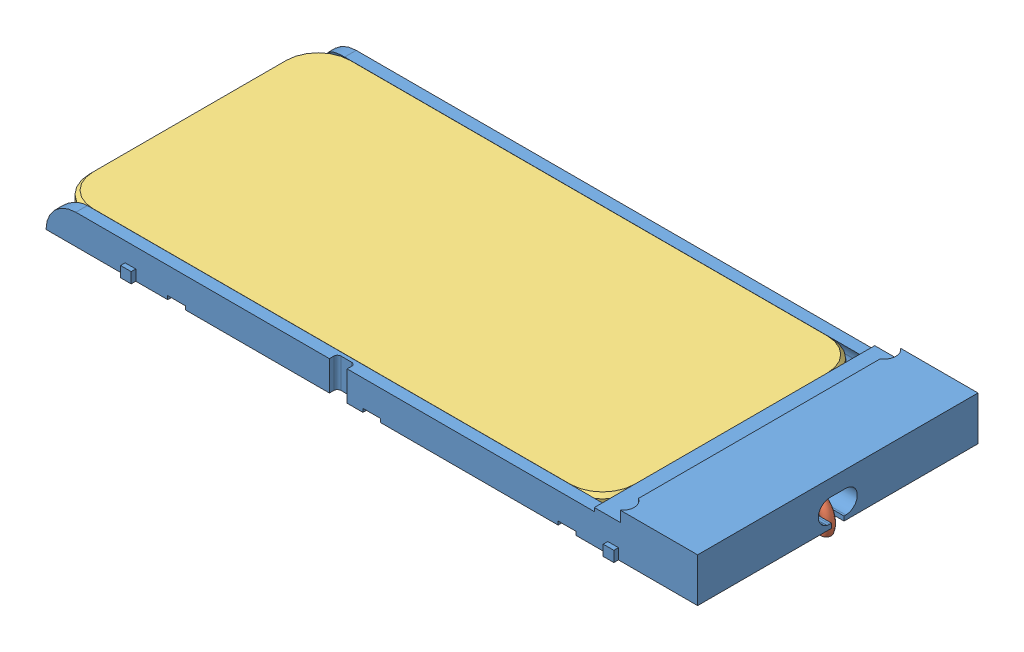
SolidWorks assembly phone-mount, configuration Default. Lengths in mm.
Overall size (183.95 29.2 81.6).
3 component instances, 3 part files, 9 mates.
Components (placement in the parent):
- phone-mount-1: phone-mount [Default] at origin size (183.95 25.78 81.6)
- phone-usb-cable-1: phone-usb-cable [Default] at (62.7 4.5 0) x (0 0 1) z (-1 0 0) size (10.6 11.2 33.23)
- phone-1: phone [Default] at (-14.55 1 0) size (154.5 8 74.4)
Mates (geometry in assembly coordinates):
- Width1: width: plane of phone-mount-1 through (57.7559 0 19.725) normal (0 0 1); plane of phone-mount-1 through (57.7559 0 30.275) normal (0 0 -1); plane of ? through (81.25 7.6 19.925) normal (0 0 -1); plane of ? through (81.25 7.6 30.075) normal (0 0 1)
- Width2: width: plane of phone-mount-1 through (57.7559 4.8 0) normal (0 1 0); plane of phone-mount-1 through (57.7559 10.4 0) normal (0 -1 0); plane of ? through (81.25 5 25) normal (0 -1 0); plane of ? through (81.25 10.2 25) normal (0 1 0)
- Coincident1: coincident: plane of phone-mount-1 through (70.5 0 0) normal (1 0 0); plane of ? through (70.5 7.6 25) normal (-1 0 0)
- Coincident2: coincident: plane of phone-mount-1 through (62.7 0 0) normal (-1 0 0); plane of phone-usb-cable-1 through (62.7 4.5 2.2) normal (-1 0 0)
- Width3: width: plane of phone-mount-1 through (91.801 1.25 0) normal (0 1 0); plane of phone-mount-1 through (91.801 7.75 0) normal (0 -1 0); plane of phone-usb-cable-1 through (77.5 7.6 2.2) normal (0 1 0); plane of phone-usb-cable-1 through (77.5 1.4 2.2) normal (0 -1 0)
- Coincident3: coincident: plane of phone-mount-1 through (0 0 0) normal (0 0 1); plane of assembly through (0 0 0) normal (0 0 1)
- Coincident4: coincident: plane of phone-usb-cable-1 through (62.7 4.5 0) normal (0 0 1); plane of assembly through (0 0 0) normal (0 0 1)
- Coincident5: coincident: line of phone-usb-cable-1 through (-11.9966 49.8907 4.5) axis (0 -1 0); line of phone-1 through (-31.6904 70.391 4.5) axis (0 1 0)
- Coincident6: coincident: plane of phone-mount-1 through (62.7 0 0) normal (-1 0 0); plane of phone-1 through (62.7 8.4 -37.2) normal (1 0 0)
